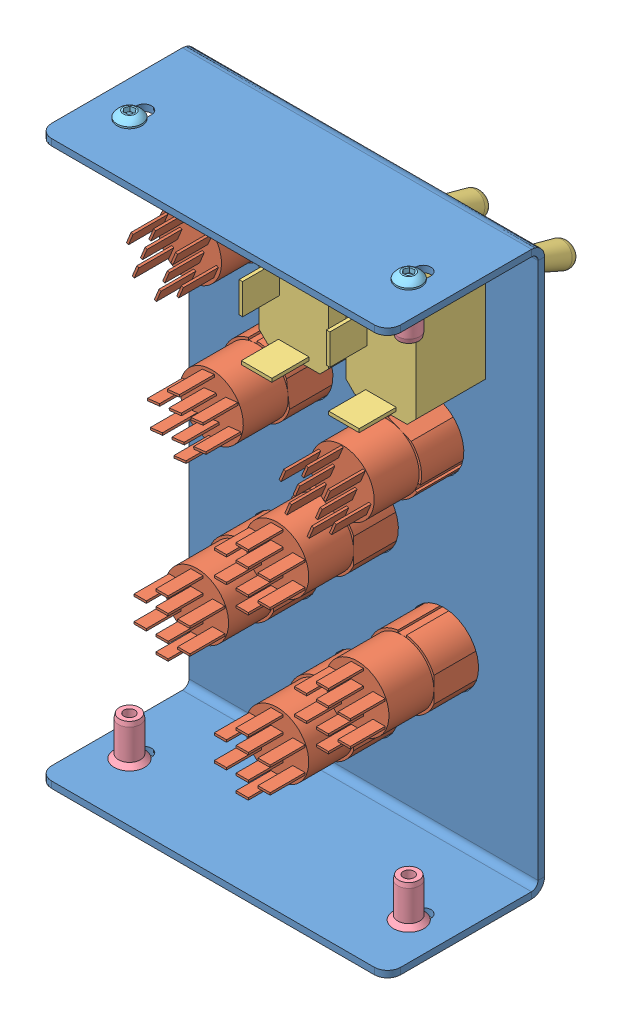
SolidWorks assembly BCV3 112 001 - Montagem controle V3, configuration Valor predeterminado. Lengths in mm.
Overall size (80 132.3 61.5).
19 component instances, 6 part files, 38 mates.
Components (placement in the parent):
- BCV3 112 101 - Controle base-1: BCV3 112 101 - Controle base [Valor predeterminado] at (-14.6327 -8.7523 17.5) size (80 125 35.5) (hidden)
- BCV3 112 108 - Controle tampa game-1: BCV3 112 108 - Controle tampa game [Valor predeterminado] at (-14.6327 -8.7523 -20.1357) x (0 -1 0) z (0 0 1) size (129 80 36)
- BCV3 112 102 - Controle botão-1: BCV3 112 102 - Controle botão [Valor predeterminado] at (-29.6327 6.2477 -21.6357) x (0.992976 0.118316 0) z (-0.118316 0.992976 0) size (17.7 39.7 17.7)
- BCV3 112 102 - Controle botão-2: BCV3 112 102 - Controle botão [Valor predeterminado] at (-33.0081 -34.8769 -21.6357) x (1 0 0) z (0 1 0) size (17.7 39.7 17.7)
- BCV3 112 102 - Controle botão-3: BCV3 112 102 - Controle botão [Valor predeterminado] at (-14.6327 -16.5014 -21.6357) x (1 0 0) z (0 1 0) size (17.7 39.7 17.7)
- BCV3 112 102 - Controle botão-5: BCV3 112 102 - Controle botão [Valor predeterminado] at (3.7427 -34.8769 -21.6357) x (1 0 0) z (0 1 0) size (17.7 39.7 17.7)
- BCV3 112 102 - Controle botão-6: BCV3 112 102 - Controle botão [Valor predeterminado] at (-14.6327 -53.2523 -21.6357) x (1 0 0) z (0 1 0) size (17.7 39.7 17.7)
- BCV3 112 102 - Controle botão-7: BCV3 112 102 - Controle botão [Valor predeterminado] at (0.3673 6.2477 -21.6357) x (-0.381234 -0.924479 0) z (0.924479 -0.381234 0) size (17.7 39.7 17.7)
- BCV3 112 102 - Controle botão-8: BCV3 112 102 - Controle botão [Valor predeterminado] at (-34.6327 35.7477 -21.6357) x (-0.381234 -0.924479 0) z (0.924479 -0.381234 0) size (17.7 39.7 17.7)
- BCV3 112 103 - Controle chave geral-1: BCV3 112 103 - Controle chave geral [Default] at (-14.6327 35.7477 -12.1357) x (-1 0 0) z (0 0 -1) size (17 29 51.5)
- BCV3 112 103 - Controle chave geral-2: BCV3 112 103 - Controle chave geral [Default] at (5.3673 35.7477 -12.1357) x (-1 0 0) z (0 0 -1) size (17 29 51.5)
- BCV3 112 106 - Controle rivkle M3-2: BCV3 112 106 - Controle rivkle M3 [Valor predeterminado] at (-46.6327 -71.2523 1.5) x (0.389066 0 0.92121) z (-0.92121 0 0.389066) size (7 9 7)
- BCV3 112 106 - Controle rivkle M3-3: BCV3 112 106 - Controle rivkle M3 [Valor predeterminado] at (17.3673 53.7477 1.5) x (0.837169 0 0.546944) z (0.546944 0 -0.837169) size (7 9 7)
- BCV3 112 106 - Controle rivkle M3-4: BCV3 112 106 - Controle rivkle M3 [Valor predeterminado] at (17.3673 -71.2523 1.5) x (-0.46521 0 0.8852) z (-0.8852 0 -0.46521) size (7 9 7)
- BCV3 112 106 - Controle rivkle M3-5: BCV3 112 106 - Controle rivkle M3 [Valor predeterminado] at (-46.6327 53.7477 1.5) x (0.837169 0 0.546944) z (0.546944 0 -0.837169) size (7 9 7)
- socket button head screw_bsi-5: socket button head screw_bsi [ISO 7380 - M3 x 8 --- 8S] at (17.3673 -74.9023 1.5) x (0 1 0) z (0.491526 0 -0.870863) size (9.65 5.7 5.7)
- socket button head screw_bsi-6: socket button head screw_bsi [ISO 7380 - M3 x 8 --- 8S] at (-46.6327 -74.9023 1.5) x (0 1 0) z (0 0 1) size (9.65 5.7 5.7)
- socket button head screw_bsi-7: socket button head screw_bsi [ISO 7380 - M3 x 8 --- 8S] at (17.3673 57.3977 1.5) x (0 -1 0) z (-0.777442 0 0.628954) size (9.65 5.7 5.7)
- socket button head screw_bsi-8: socket button head screw_bsi [ISO 7380 - M3 x 8 --- 8S] at (-46.6327 57.3977 1.5) x (0 -1 0) z (-0.777442 0 0.628954) size (9.65 5.7 5.7)
Mates (geometry in assembly coordinates):
- Largura1: width anti-aligned: plane of BCV3 112 108 - Controle tampa game-1 through (25.3673 -73.2523 -18.6357) normal (1 0 0); plane of BCV3 112 108 - Controle tampa game-1 through (-54.6327 55.7477 -18.6357) normal (-1 0 0); plane of BCV3 112 101 - Controle base-1 through (-54.6327 53.7477 17.5) normal (-1 0 0); plane of BCV3 112 101 - Controle base-1 through (25.3673 53.7477 17.5) normal (1 0 0)
- Largura3: width aligned: plane of BCV3 112 108 - Controle tampa game-1 through (25.3673 -71.7523 -20.1357) normal (0 1 0); plane of BCV3 112 108 - Controle tampa game-1 through (25.3673 54.2477 -20.1357) normal (0 -1 0); plane of BCV3 112 101 - Controle base-1 through (-51.6327 53.7477 16) normal (0 1 0); plane of BCV3 112 101 - Controle base-1 through (-51.6327 -71.2523 16) normal (0 -1 0)
- Coincidente1: coincident anti-aligned: plane of BCV3 112 108 - Controle tampa game-1 through (25.3673 54.2477 -21.6357) normal (0 0 -1); plane of BCV3 112 102 - Controle botão-7 through (0.3673 6.2477 -21.6357) normal (0 0 1)
- Coincidente2: coincident anti-aligned: plane of BCV3 112 108 - Controle tampa game-1 through (25.3673 54.2477 -21.6357) normal (0 0 -1); plane of BCV3 112 102 - Controle botão-1 through (-29.6327 6.2477 -21.6357) normal (0 0 1)
- Coincidente3: coincident anti-aligned: plane of BCV3 112 108 - Controle tampa game-1 through (25.3673 54.2477 -21.6357) normal (0 0 -1); plane of BCV3 112 102 - Controle botão-2 through (-33.0081 -34.8769 -21.6357) normal (0 0 1)
- Coincidente4: coincident anti-aligned: plane of BCV3 112 108 - Controle tampa game-1 through (25.3673 54.2477 -21.6357) normal (0 0 -1); plane of BCV3 112 102 - Controle botão-3 through (-14.6327 -16.5014 -21.6357) normal (0 0 1)
- Coincidente5: coincident anti-aligned: plane of BCV3 112 108 - Controle tampa game-1 through (25.3673 54.2477 -21.6357) normal (0 0 -1); plane of BCV3 112 102 - Controle botão-6 through (-14.6327 -53.2523 -21.6357) normal (0 0 1)
- Coincidente6: coincident anti-aligned: plane of BCV3 112 108 - Controle tampa game-1 through (25.3673 54.2477 -21.6357) normal (0 0 -1); plane of BCV3 112 102 - Controle botão-5 through (3.7427 -34.8769 -21.6357) normal (0 0 1)
- Coincidente7: coincident anti-aligned: plane of BCV3 112 108 - Controle tampa game-1 through (25.3673 54.2477 -21.6357) normal (0 0 -1); plane of BCV3 112 102 - Controle botão-8 through (-34.6327 35.7477 -21.6357) normal (0 0 1)
- Coincidente8: coincident anti-aligned: plane of BCV3 112 108 - Controle tampa game-1 through (25.3673 54.2477 -21.6357) normal (0 0 -1); plane of BCV3 112 103 - Controle chave geral-2 through (5.3673 45.5627 -21.6357) normal (0 0 1)
- Coincidente9: coincident anti-aligned: plane of BCV3 112 108 - Controle tampa game-1 through (25.3673 54.2477 -21.6357) normal (0 0 -1); plane of BCV3 112 103 - Controle chave geral-1 through (-14.6327 45.5627 -21.6357) normal (0 0 1)
- Paralelo1: parallel aligned: plane of BCV3 112 108 - Controle tampa game-1 through (25.3673 55.7477 -20.1357) normal (0 1 0); plane of BCV3 112 103 - Controle chave geral-1 through (-13.6327 40.5977 -20.6357) normal (0 1 0)
- Paralelo2: parallel aligned: plane of BCV3 112 108 - Controle tampa game-1 through (25.3673 55.7477 -20.1357) normal (0 1 0); plane of BCV3 112 103 - Controle chave geral-2 through (6.3673 40.5977 -20.6357) normal (0 1 0)
- Coincidente30: coincident anti-aligned: plane of BCV3 112 108 - Controle tampa game-1 through (25.3673 -73.2523 -20.1357) normal (0 -1 0); plane of socket button head screw_bsi-6 through (-48.1327 -73.2523 1.5) normal (0 1 0)
- Coincidente31: coincident anti-aligned: plane of BCV3 112 108 - Controle tampa game-1 through (25.3673 -73.2523 -20.1357) normal (0 -1 0); plane of socket button head screw_bsi-5 through (18.6736 -73.2523 2.2373) normal (0 1 0)
- Coincidente32: coincident anti-aligned: plane of BCV3 112 108 - Controle tampa game-1 through (25.3673 55.7477 -20.1357) normal (0 1 0); plane of socket button head screw_bsi-7 through (18.3107 55.7477 2.6662) normal (0 -1 0)
- Coincidente33: coincident anti-aligned: plane of BCV3 112 108 - Controle tampa game-1 through (25.3673 55.7477 -20.1357) normal (0 1 0); plane of socket button head screw_bsi-8 through (-45.6893 55.7477 2.6662) normal (0 -1 0)
- Concêntrico55: concentric anti-aligned: cylinder of BCV3 112 108 - Controle tampa game-1 through (-14.6327 35.7477 2.4917) axis (0 0 -1) radius 6; cylinder of BCV3 112 103 - Controle chave geral-1 through (-14.6327 35.7477 -33.1357) axis (0 0 1) radius 5.85
- Concêntrico57: concentric anti-aligned: cylinder of BCV3 112 108 - Controle tampa game-1 through (-29.6327 6.2477 2.4917) axis (0 0 -1) radius 8; cylinder of BCV3 112 102 - Controle botão-1 through (-29.6327 6.2477 -28.0357) axis (0 0 1) radius 8.85
- Concêntrico58: concentric anti-aligned: cylinder of BCV3 112 108 - Controle tampa game-1 through (0.3673 6.2477 2.4917) axis (0 0 -1) radius 8; cylinder of BCV3 112 102 - Controle botão-7 through (0.3673 6.2477 -28.0357) axis (0 0 1) radius 8.85
- Concêntrico59: concentric anti-aligned: cylinder of BCV3 112 108 - Controle tampa game-1 through (-14.6327 -16.5014 2.4917) axis (0 0 -1) radius 8; cylinder of BCV3 112 102 - Controle botão-3 through (-14.6327 -16.5014 -28.0357) axis (0 0 1) radius 8.85
- Concêntrico60: concentric anti-aligned: cylinder of BCV3 112 108 - Controle tampa game-1 through (3.7427 -34.8769 2.4917) axis (0 0 -1) radius 8; cylinder of BCV3 112 102 - Controle botão-5 through (3.7427 -34.8769 -28.0357) axis (0 0 1) radius 8.85
- Concêntrico61: concentric anti-aligned: cylinder of BCV3 112 108 - Controle tampa game-1 through (-14.6327 -53.2523 2.4917) axis (0 0 -1) radius 8; cylinder of BCV3 112 102 - Controle botão-6 through (-14.6327 -53.2523 -28.0357) axis (0 0 1) radius 8.85
- Concêntrico62: concentric anti-aligned: cylinder of BCV3 112 108 - Controle tampa game-1 through (-33.0081 -34.8769 2.4917) axis (0 0 -1) radius 8; cylinder of BCV3 112 102 - Controle botão-2 through (-33.0081 -34.8769 -28.0357) axis (0 0 1) radius 8.85
- Concêntrico74: concentric anti-aligned: cylinder of BCV3 112 108 - Controle tampa game-1 through (5.3673 35.7477 2.4917) axis (0 0 -1) radius 6; cylinder of BCV3 112 103 - Controle chave geral-2 through (5.3673 35.7477 -33.1357) axis (0 0 1) radius 5.85
- Concêntrico75: concentric anti-aligned: cylinder of BCV3 112 108 - Controle tampa game-1 through (-34.6327 35.7477 2.4917) axis (0 0 -1) radius 8; cylinder of BCV3 112 102 - Controle botão-8 through (-34.6327 35.7477 -32.0357) axis (0 0 1) radius 7.75
- Coincidente44: coincident aligned: plane of BCV3 112 101 - Controle base-1 through (-53.1327 53.7477 -18) normal (0 1 0); plane of BCV3 112 106 - Controle rivkle M3-5 through (-53.1973 53.7477 -2.7888) normal (0 1 0)
- Concêntrico76: concentric anti-aligned: cylinder of BCV3 112 101 - Controle base-1 through (-46.6327 53.7477 1.5) axis (0 -1 0) radius 2.5; cylinder of BCV3 112 106 - Controle rivkle M3-5 through (-46.6327 44.7477 1.5) axis (0 1 0) radius 2.5
- Concêntrico77: concentric anti-aligned: cylinder of BCV3 112 101 - Controle base-1 through (17.3673 53.7477 1.5) axis (0 -1 0) radius 2.5; cylinder of BCV3 112 106 - Controle rivkle M3-3 through (17.3673 44.7477 1.5) axis (0 1 0) radius 2.5
- Coincidente45: coincident aligned: plane of BCV3 112 101 - Controle base-1 through (23.8673 53.7477 14.5) normal (0 1 0); plane of BCV3 112 106 - Controle rivkle M3-3 through (10.8027 53.7477 -2.7888) normal (0 1 0)
- Coincidente47: coincident aligned: plane of BCV3 112 101 - Controle base-1 through (-53.1327 -71.2523 -18) normal (0 -1 0); plane of BCV3 112 106 - Controle rivkle M3-2 through (-49.6836 -71.2523 -5.7236) normal (0 -1 0)
- Concêntrico78: concentric aligned: cylinder of BCV3 112 101 - Controle base-1 through (-46.6327 53.7477 1.5) axis (0 -1 0) radius 2.5; cylinder of BCV3 112 106 - Controle rivkle M3-2 through (-46.6327 -62.2523 1.5) axis (0 -1 0) radius 2.5
- Concêntrico79: concentric aligned: cylinder of BCV3 112 101 - Controle base-1 through (17.3673 53.7477 1.5) axis (0 -1 0) radius 2.5; cylinder of BCV3 112 106 - Controle rivkle M3-4 through (17.3673 -62.2523 1.5) axis (0 -1 0) radius 2.5
- Coincidente48: coincident aligned: plane of BCV3 112 101 - Controle base-1 through (23.8673 -71.2523 14.5) normal (0 -1 0); plane of BCV3 112 106 - Controle rivkle M3-4 through (21.0152 -71.2523 -5.4412) normal (0 -1 0)
- Concêntrico80: concentric aligned: cylinder of BCV3 112 106 - Controle rivkle M3-3 through (17.3673 49.7477 1.5) axis (0 1 0) radius 1.6; cylinder of socket button head screw_bsi-7 through (17.3673 57.3977 1.5) axis (0 1 0) radius 1.5
- Concêntrico81: concentric aligned: cylinder of BCV3 112 106 - Controle rivkle M3-5 through (-46.6327 49.7477 1.5) axis (0 1 0) radius 1.6; cylinder of socket button head screw_bsi-8 through (-46.6327 57.3977 1.5) axis (0 1 0) radius 1.5
- Concêntrico82: concentric aligned: cylinder of BCV3 112 106 - Controle rivkle M3-2 through (-46.6327 -67.2523 1.5) axis (0 -1 0) radius 1.6; cylinder of socket button head screw_bsi-6 through (-46.6327 -74.9023 1.5) axis (0 -1 0) radius 1.5
- Concêntrico83: concentric aligned: cylinder of BCV3 112 106 - Controle rivkle M3-4 through (17.3673 -67.2523 1.5) axis (0 -1 0) radius 1.6; cylinder of socket button head screw_bsi-5 through (17.3673 -74.9023 1.5) axis (0 -1 0) radius 1.5
